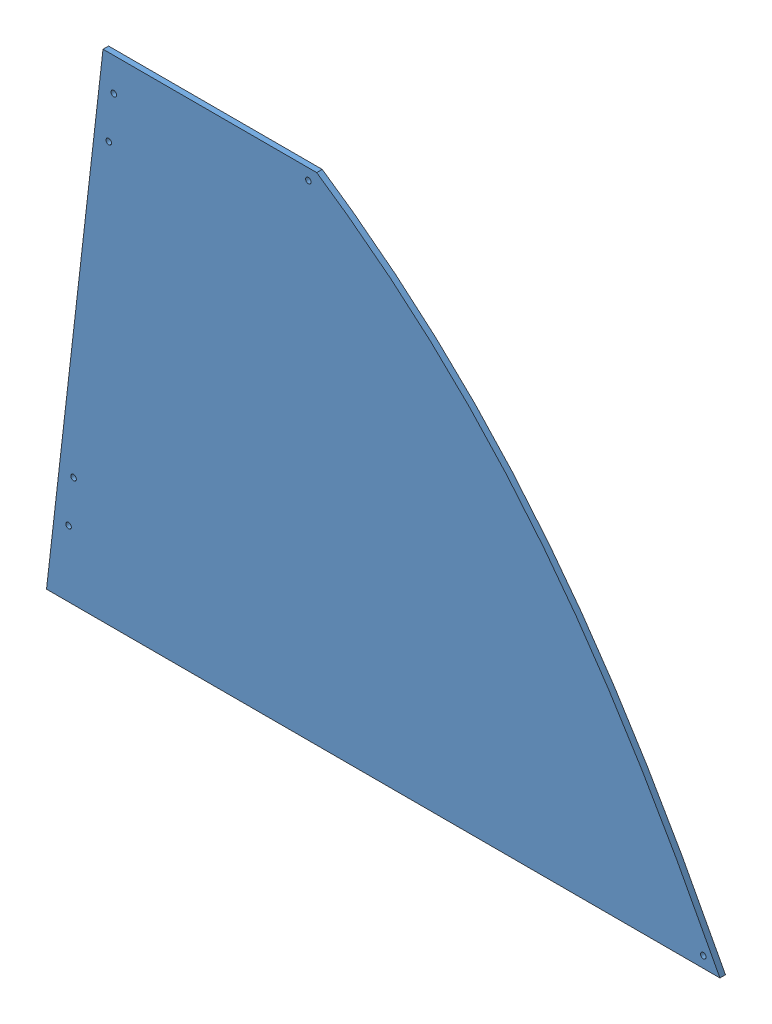
SolidWorks assembly GE-19080-Left-Blue, configuration Default. Lengths in mm.
Overall size (771.1 567.83 44.58).
2 component instances, 2 part files, 3 mates.
Components (placement in the parent):
- GE-19080-1: GE-19080 [GE-19080] at origin size (771.1 567.83 6.35)
- GE-19080-Left-Blue-Vinyl-1: GE-19080-Left-Blue-Vinyl [Notched] at (0 0 -0.127) size (771.1 567.83 0.13)
Mates (geometry in assembly coordinates):
- Coincident1: coincident: plane of assembly; line of assembly; plane of GE-19080-1 through (546.1766 314.686 0) normal (0 0 -1); line of GE-19080-Left-Blue-Vinyl-1 through (571.5 49.357 567.8263) axis (0 -0.113203 -0.993572)
- Coincident2: coincident: plane of assembly; plane of assembly; plane of GE-19080-1 through (64.6956 567.8263 6.35) normal (0 1 0); plane of GE-19080-Left-Blue-Vinyl-1 through (64.6956 567.8263 0) normal (0 1 0)
- Coincident3: coincident: plane of assembly; plane of assembly; plane of GE-19080-1 through (32.7402 567.8263 582.3432) normal (-0.993572 0.113203 0); plane of GE-19080-Left-Blue-Vinyl-1 through (32.7402 567.8263 575.9932) normal (-0.993572 0.113203 0)
